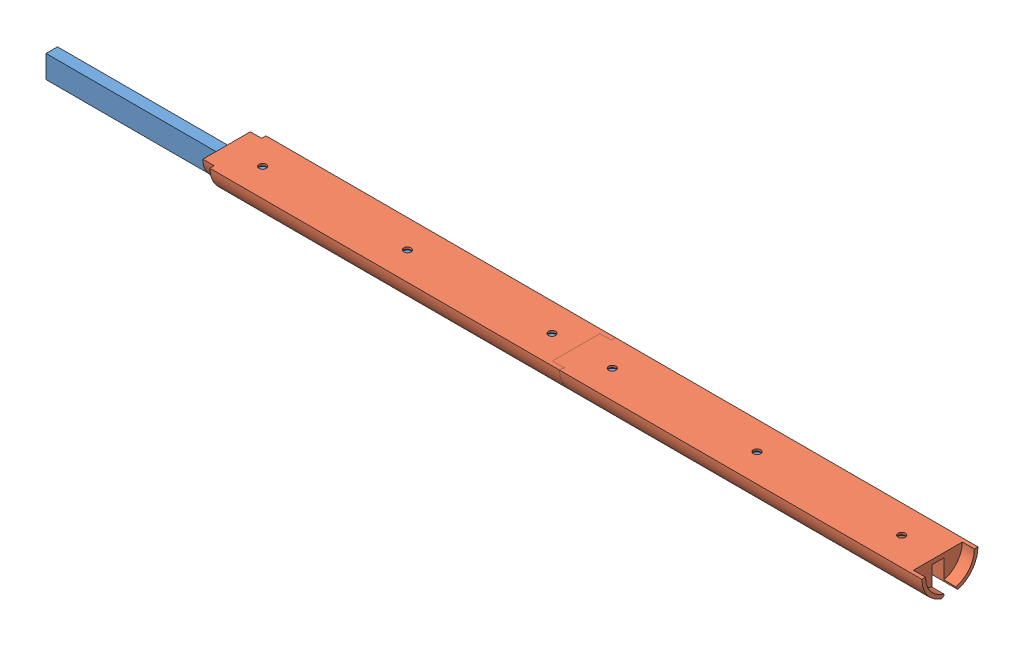
SolidWorks assembly Assem1, configuration Default. Lengths in mm.
Overall size (469.9 25.73 28.34).
3 component instances, 2 part files, 8 mates.
Components (placement in the parent):
- Aclorol LED Neon Rope Lights Addressable LED Strip-2: Aclorol LED Neon Rope Lights Addressable LED Strip [Default] at origin size (381 11.94 6.05)
- Ceiling LED Mount V2-1: Ceiling LED Mount V2 [Default] x (0 0 -1) z (1 0 0) size (29.58 14.17 196.85)
- Ceiling LED Mount V2-2: Ceiling LED Mount V2 [Default] at (184.15 0 0) x (0 0 -1) z (1 0 0) size (29.58 14.17 196.85)
Mates (geometry in assembly coordinates):
- Coincident1: coordinate: point of Aclorol LED Neon Rope Lights Addressable LED Strip-2
- InPlace1: in place: plane of Ceiling LED Mount V2-1 through (0 0 0) normal (1 0 0); moOrthogonalPlaneRef_w of Ceiling LED Mount V2-1 through (0 0 0) normal (0 1 0); plane of Ceiling LED Mount V2-1 through (0 0 0) normal (0 0 -1); unknown of Ceiling LED Mount V2-1
- Coincident2: coincident aligned: 
- Coincident3: coincident aligned: plane of Part3^Assem1-1 through (0 0 0) normal (0 1 0)
- Coincident4: coincident anti-aligned: plane of Part3^Assem1-1 through (0 0 0) normal (0 0 -1)
- Coincident5: coincident anti-aligned: plane of Part3^Assem1-1 through (88.9 0 0) normal (1 0 0); plane of Part3^Assem1-2 through (88.9 0 0) normal (-1 0 0)
- Coincident6: coincident aligned: plane of Part3^Assem1-1 through (95.25 7.874 0) normal (0 1 0); plane of Part3^Assem1-2 through (279.4 7.874 0) normal (0 1 0)
- Concentric1: concentric aligned: cylinder of Part3^Assem1-1 through (95.25 7.874 0) axis (-1 0 0) radius 14.1691; cylinder of Part3^Assem1-2 through (279.4 7.874 0) axis (-1 0 0) radius 14.1691
